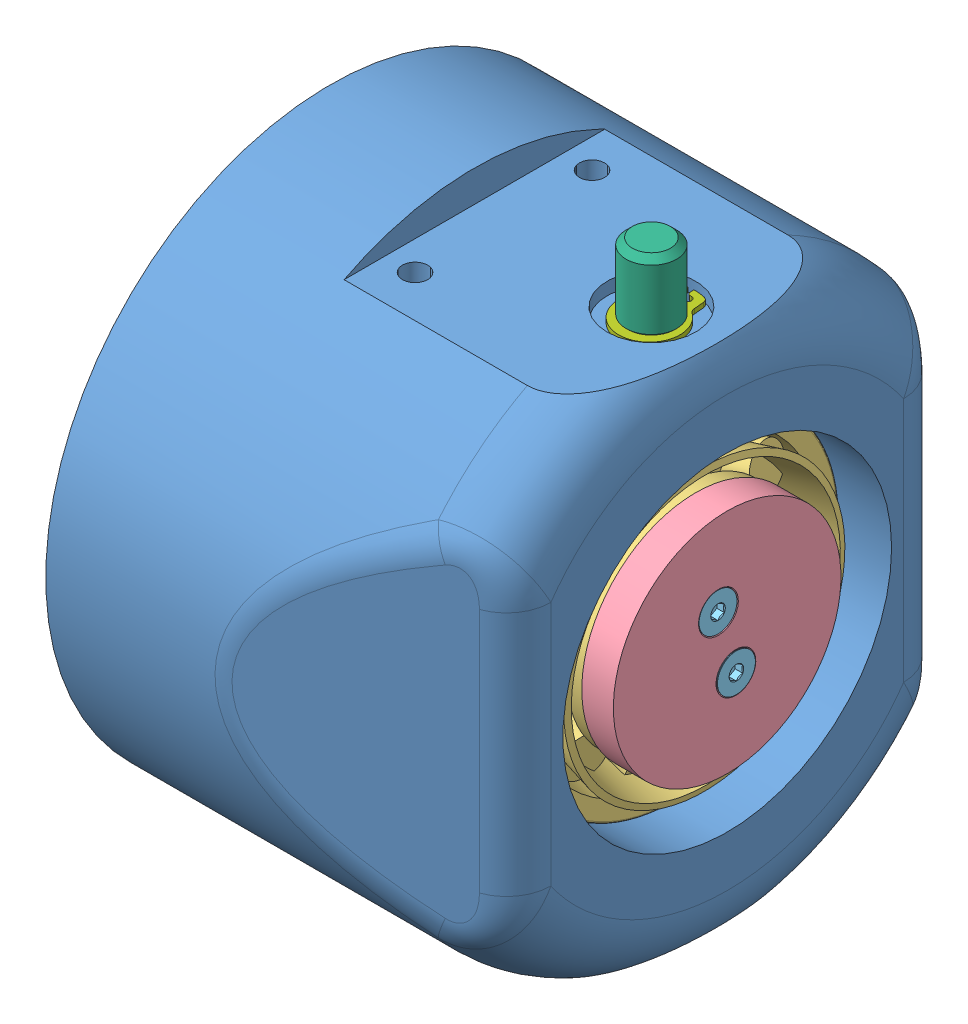
SolidWorks assembly RotationUnit, configuration Default. Lengths in mm.
Overall size (79.33 94.5 90).
9 component instances, 7 part files, 10 mates.
Components (placement in the parent):
- rotatingPart^RotationUnit-1: rotatingPart^RotationUnit [Default] at origin size (63.63 90 90) (virtual)
- Copy of axis^RotationUnit-1: Copy of axis^RotationUnit [Default] at (-47.25 0 0) x (1 0 0) z (0 -0.2761 0.961129) size (73 36 36) (virtual)
- 6677K87_Tapered-Roller Bearing with Steel Ring-1: 6677K87_Tapered-Roller Bearing with Steel Ring [6677K87] at (16.5 0 0) x (0 0.225972 0.974134) z (-1 0 0) size (52 52 19.81)
- 6677K87_Tapered-Roller Bearing with Steel Ring-2: 6677K87_Tapered-Roller Bearing with Steel Ring [6677K87] at (-16.5 0 0) x (0 0 1) z (1 0 0) size (52 52 19.81)
- Part1^RotationUnit-1: Part1^RotationUnit [Default] at (26.25 0 0) x (0 -0.2761 0.961129) z (0 0.961129 0.2761) size (36 5 36) (virtual)
- 92125A130_18-8 Stainless Steel Hex Drive Flat Head Screw-1: 92125A130_18-8 Stainless Steel Hex Drive Flat Head Screw [92125A130] at (26.335 -4.8056 -1.3805) x (0 0 -1) z (1 0 0) size (6 6 10.3)
- 92125A130_18-8 Stainless Steel Hex Drive Flat Head Screw-2: 92125A130_18-8 Stainless Steel Hex Drive Flat Head Screw [92125A130] at (26.185 4.8056 1.3805) x (0 0 -1) z (1 0 0) size (6 6 10.3)
- Part2^RotationUnit-1: Part2^RotationUnit [Default] at (19.2645 38.5 0) x (0 -1 0) z (0 0 1) size (22 8 8) (virtual)
- 90154A137_External Retaining Ring-1: 90154A137_External Retaining Ring [90154A137] at (19.2645 38.375 0) x (0.995938 0 -0.090045) z (0 -1 0) size (9.68 12.1 0.75)
Mates (geometry in assembly coordinates):
- Concentric9: concentric anti-aligned: cylinder of 6677K87_Tapered-Roller Bearing with Steel Ring-1 through (11.25 0 0) axis (-1 0 0) radius 10; cylinder of 6677K87_Tapered-Roller Bearing with Steel Ring-2 through (-11.25 0 0) axis (1 0 0) radius 10
- Concentric14: concentric anti-aligned: cylinder of 6677K87_Tapered-Roller Bearing with Steel Ring-2 through (-11.25 0 0) axis (1 0 0) radius 10; cylinder of Copy of axis^RotationUnit_Wrist-Rev1-1 through (-47.25 0 0) axis (-1 0 0) radius 10
- Coincident14: coincident anti-aligned: plane of 6677K87_Tapered-Roller Bearing with Steel Ring-2 through (-26.25 -10 0) normal (-1 0 0); plane of Copy of axis^RotationUnit_Wrist-Rev1-1 through (-26.25 0 0) normal (1 0 0)
- Coincident15: coincident anti-aligned: plane of 6677K87_Tapered-Roller Bearing with Steel Ring-1 through (26.25 9.7413 -2.2597) normal (1 0 0); plane of Part1^RotationUnit_Wrist-Rev1-1 through (26.25 0 0) normal (-1 0 0)
- Concentric15: concentric aligned: cylinder of 6677K87_Tapered-Roller Bearing with Steel Ring-1 through (11.25 0 0) axis (-1 0 0) radius 17.5184; cylinder of Part1^RotationUnit_Wrist-Rev1-1 through (31.25 0 0) axis (-1 0 0) radius 18
- Concentric16: concentric aligned: cone of Part1^RotationUnit_Wrist-Rev1-1 through (31.25 -4.8056 -1.3805) axis (-1 0 0); cone of 92125A130_18-8 Stainless Steel Hex Drive Flat Head Screw-1 through (31.25 -4.8056 -1.3805) axis (-1 0 0)
- Coincident17: coincident aligned: cone of Part1^RotationUnit_Wrist-Rev1-1 through (31.25 4.8056 1.3805) axis (-1 0 0); cone of 92125A130_18-8 Stainless Steel Hex Drive Flat Head Screw-2 through (31.1 4.8056 1.3805) axis (-1 0 0)
- Concentric17: concentric aligned: cylinder of Copy of axis^RotationUnit_Wrist-Rev1-1 through (25.75 -4.8056 -1.3805) axis (1 0 0) radius 1.25; cylinder of Part1^RotationUnit_Wrist-Rev1-1 through (31.25 -4.8056 -1.3805) axis (1 0 0) radius 1.6
- Concentric19: concentric anti-aligned: cylinder of Part2^RotationUnit_Wrist-Rev1-1 through (19.2645 27.5 0) axis (0 -1 0) radius 3.75; cylinder of 90154A137_External Retaining Ring-1 through (19.2645 38 0) axis (0 1 0) radius 3.7
- Coincident18: coincident anti-aligned: plane of Part2^RotationUnit_Wrist-Rev1-1 through (23.0145 38 0) normal (0 1 0); plane of 90154A137_External Retaining Ring-1 through (19.2968 38 0.3571) normal (0 -1 0)
